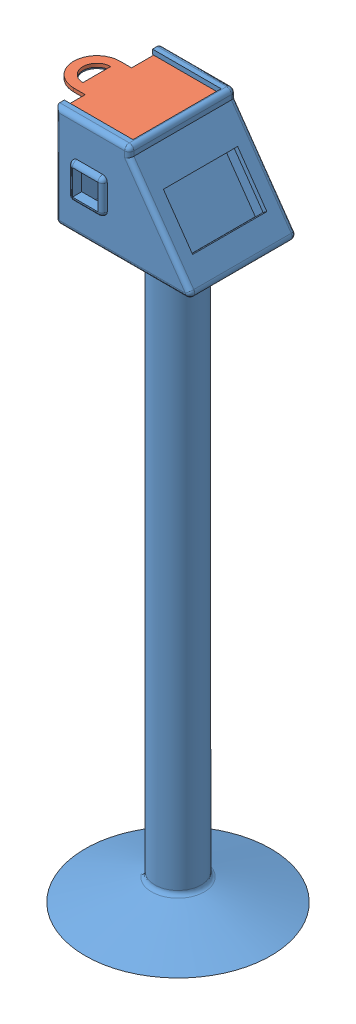
SolidWorks assembly Combine, configuration Default. Lengths in mm.
Overall size (477.18 1470 447.21).
2 component instances, 2 part files, 3 mates.
Components (placement in the parent):
- Stand & Face-1: Stand & Face [Default] at (130.254 1200.6701 1054.6221) size (477.18 1470 447.21)
- Cover-1: Cover [Default] at (280.254 1400.6701 949.6221) size (225 7.5 210)
Mates (geometry in assembly coordinates):
- Concentric4: concentric anti-aligned: cylinder of Part2-1 through (105.254 1398.1701 1054.6221) axis (0 1 0) radius 30; cylinder of Part3-1 through (105.254 1408.1701 1054.6221) axis (0 -1 0) radius 30
- Coincident4: coincident anti-aligned: plane of Part2-1 through (130.254 1400.6701 1169.6221) normal (0 1 0); plane of Part3-1 through (105.254 1400.6701 1054.6221) normal (0 -1 0)
- Coincident5: coincident anti-aligned: plane of Part2-1 through (130.254 1200.6701 1159.6221) normal (0 0 -1); plane of Part3-1 through (280.254 1408.1701 1159.6221) normal (0 0 1)
